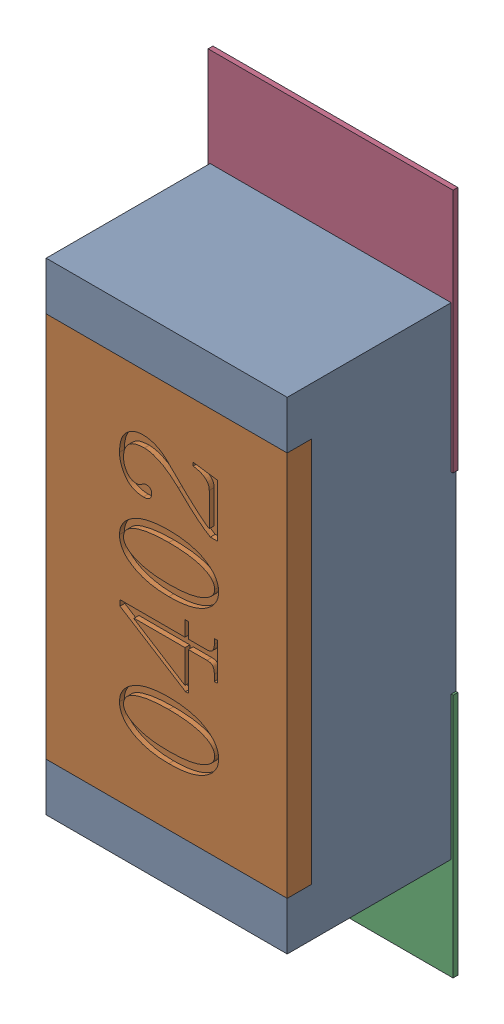
SolidWorks assembly R146, configuration Défaut. Lengths in mm.
Overall size (0.51 1.42 0.35).
5 component instances, 2 part files, 0 mates.
Components (placement in the parent):
- R0402-1: R0402 [Défaut] at (19.6343 -22.04 0) x (0 1 0) z (0 0 1) size (1 0.5 0.35)
- 6504207776-1: 6504207776 [Défaut] at (19.6342 -22.4971 0) size (0.51 0.51 0.01)
  - Extruded-1: Extruded [Défaut] at origin size (0.51 0.51 0.01)
- 6504207776-2: 6504207776 [Défaut] at (19.6342 -21.59 0) size (0.51 0.51 0.01)
  - Extruded-1: Extruded [Défaut] at origin size (0.51 0.51 0.01)
